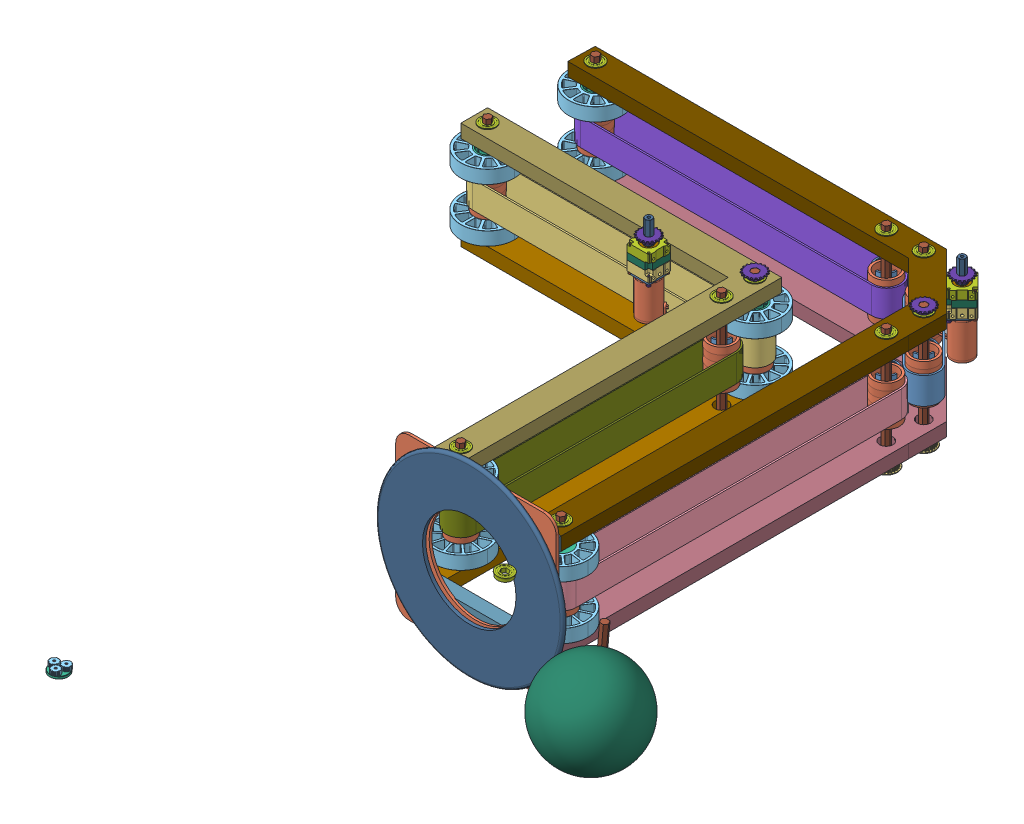
SolidWorks assembly Iteration3_v4, configuration Default. Lengths in mm.
Overall size (1189.44 656.85 1138.64).
276 component instances, 40 part files, 0 mates.
Components (placement in the parent):
- Iteration3_v4.step-1: Iteration3_v4.step [Default] at origin size (1189.44 656.85 1138.64)
  - Assembly 3 _2_.step-1: Assembly 3 _2_.step [Default] at origin size (67.31 38.1 67.31)
    - 2in Wheel Intergrated 0500 HEX Hub.STEP-1: 2in Wheel Intergrated 0500 HEX Hub.STEP [Default] at (23.3322 453.8443 -103.7275) x (1 0 0) z (0 -1 0) size (41.91 41.91 25.4)
    - 2in Tread.step-1: 2in Tread.step [Default] at (23.3322 453.8443 -103.7275) x (1 0 0) z (0 -1 0) size (50.8 50.8 25.4)
  - Assembly 3 _30_.step-1: Assembly 3 _30_.step [Default] at origin size (67.31 38.1 67.31)
    - 2in Tread.step-1: 2in Tread.step [Default] at (745.6616 401.2663 66.1079) x (1 0 0) z (0 -1 0) size (50.8 50.8 25.4)
    - 2in Wheel Intergrated 0500 HEX Hub.STEP-1: 2in Wheel Intergrated 0500 HEX Hub.STEP [Default] at (745.6616 401.2663 66.1079) x (1 0 0) z (0 -1 0) size (41.91 41.91 25.4)
  - belt pulley _4_.step-1: belt pulley _4_.step [Default] at origin size (42 14 42)
    - am-3403 24 tooth HTD pulley half 500hex.step-1: am-3403 24 tooth HTD pulley half 500hex.step [Default] at (745.7172 329.5288 -5.0591) x (0 1 0) z (-1 0 0) size (8.91 42 42)
    - am-3403 24 tooth HTD pulley half 500hex.step-2: am-3403 24 tooth HTD pulley half 500hex.step [Default] at (787.7172 329.5288 -5.0591) x (0 -1 0) z (1 0 0) size (8.91 42 42)
  - 217-4973_1stage_BAG _1_.step-1: 217-4973_1stage_BAG _1_.step [Default] at origin size (852.63 623.39 984.66)
    - 217-2820 Rev1_Public _1_.step-1: 217-2820 Rev1_Public _1_.step [Default] at origin size (852.63 582.79 973.43)
      - 217-2625-100 _1_.step-1: 217-2625-100 _1_.step [Default] at origin size (48.74 12.7 48.74)
        - 217-2625-010 Rev1.step-1: 217-2625-010 Rev1.step [Default] at (-51.7575 -31.3954 849.6821) x (0.784104 0 0.62063) z (0 1 0) size (4 4 12)
        - 217-2625-005 Rev1_Planet_Revolving_Follower01.step-1: 217-2625-005 Rev1_Planet_Revolving_Follower01.step [Default] at (-38.1283 -28.6954 860.4699) x (0.955071 0 0.296378) z (0 1 0) size (16.91 16.91 8)
        - 217-2625-010 Rev1.step-2: 217-2625-010 Rev1.step [Default] at (-35.3114 -31.3954 842.9076) x (0.795957 0 0.605353) z (0 1 0) size (4 4 12)
        - 217-2625-005 Rev1_Planet_Revolving_Follower01.step-2: 217-2625-005 Rev1_Planet_Revolving_Follower01.step [Default] at (-35.3114 -28.6954 842.9076) x (0.979261 0 0.202601) z (0 1 0) size (16.91 16.91 8)
        - 217-2625-010 Rev1.step-3: 217-2625-010 Rev1.step [Default] at (-38.1283 -31.3954 860.4699) x (0.784104 0 0.62063) z (0 1 0) size (4 4 12)
        - 217-2625-005 Rev1_Planet_Revolving_Follower01.step-3: 217-2625-005 Rev1_Planet_Revolving_Follower01.step [Default] at (-51.7575 -28.6954 849.6821) x (-0.955094 0 -0.296304) z (0 1 0) size (16.91 16.91 8)
        - 217-2625-008 Rev1.step-1: 217-2625-008 Rev1.step [Default] at (-41.6375 -35.0454 850.9) x (0.784104 0 0.62063) z (0 1 0) size (34.7 34.7 4.7)
      - 217-2625-026 Rev1.step-1: 217-2625-026 Rev1.step [Default] at (756.0539 522.2743 -67.5963) x (-0.707171 0 -0.707043) z (0 -1 0) size (44.45 42 18.12)
      - 217-2625-007 Rev1_Public.step-1: 217-2625-007 Rev1_Public.step [Default] at (756.0539 517.4197 -67.5963) x (0.418293 0 -0.908312) z (0 -1 0) size (15.29 15.29 12.7)
    - 217-2742-001 Rev4.step-1: 217-2742-001 Rev4.step [Default] at (756.0539 536.9745 -67.5963) x (0 1 0) z (0.707043 0 -0.707171) size (7 28 28)
    - 217-2625-003 Rev1.step-1: 217-2625-003 Rev1.step [Default] at (756.0539 536.2221 -67.5963) x (-0.707171 0 -0.707043) z (0 1 0) size (17 17 64.13)
    - 832-1750-Ring-Gear-Screw_SSA0832-0500ZC.step-1: 832-1750-Ring-Gear-Screw_SSA0832-0500ZC.step [Default] at (780.8026 498.0743 -67.5986) x (0.711223 0 -0.702967) z (-0.702967 0 -0.711223) size (6.73 48.51 6.73)
    - 217-4649-001 Rev1.step-1: 217-4649-001 Rev1.step [Default] at (756.0539 508.7283 -67.5963) x (-0.707171 0 -0.707043) z (0 1 0) size (18 18 13)
    - 217-2625-011 Rev1.step-1: 217-2625-011 Rev1.step [Default] at (756.0539 503.9925 -67.5963) x (0.707043 0 -0.707171) z (-0.707171 0 -0.707043) size (8.01 7.5 7.94)
    - 217-4649-007 Rev1_94105A824.step-1: 217-4649-007 Rev1_94105A824.step [Default] at (751.2576 503.2533 -62.7993) x (-0.062366 -0.996104 -0.062355) z (-0.707043 0 0.707171) size (4.83 4.83 4.77)
    - 217-2816-001 Rev1.step-1: 217-2816-001 Rev1.step [Default] at (756.0539 522.4243 -67.5963) x (-0.707171 0 -0.707043) z (0 1 0) size (42 42 14.52)
    - 217-2625-017 Rev1_9714K61.step-1: 217-2625-017 Rev1_9714K61.step [Default] at (755.8652 536.1943 -67.3014) x (0.983376 0 -0.181581) z (-0.181581 0 -0.983376) size (28.51 4.98 27.43)
    - 217-4649-002 Rev1_SSA0832-0500ZC.step-1: 217-4649-002 Rev1_SSA0832-0500ZC.step [Default] at (756.0516 495.0743 -92.9963) x (-0.426003 0 0.904722) z (0.904722 0 0.426003) size (6.73 16.76 6.73)
    - 217-4649-006 Rev1_SSA0004-008BA.step-1: 217-4649-006 Rev1_SSA0004-008BA.step [Default] at (747.2158 498.0743 -58.7567) x (0.258731 0 -0.965949) z (0.965949 0 0.258731) size (7 14 7)
    - 217-2822-003 Rev4.step-1: 217-2822-003 Rev4.step [Default] at (756.0539 496.5743 -67.5963) x (-0.707171 0 -0.707043) z (0 -1 0) size (42 42 4.8)
    - 217-4649-002 Rev1_SSA0832-0500ZC.step-2: 217-4649-002 Rev1_SSA0832-0500ZC.step [Default] at (756.0562 495.0743 -42.1964) x (-0.890925 0 0.454151) z (0.454151 0 0.890925) size (6.73 16.76 6.73)
    - 217-3351 Rev2.step-1: 217-3351 Rev2.step [Default] at (756.0539 495.0743 -67.5963) x (0.707043 0 -0.707171) z (0 1 0) size (59.1 59.1 84.5)
    - 217-2742-001 Rev4.step-2: 217-2742-001 Rev4.step [Default] at (756.0539 528.9745 -67.5963) x (0 1 0) z (0.6385 0 -0.769622) size (7 28 28)
    - 217-2625-025 Rev1.step-1: 217-2625-025 Rev1.step [Default] at (756.0539 505.5743 -67.5963) x (-0.707171 0 -0.707043) z (0 -1 0) size (44.45 42 18)
    - 217-4649-006 Rev1_SSA0004-008BA.step-2: 217-4649-006 Rev1_SSA0004-008BA.step [Default] at (764.8919 498.0743 -76.436) x (-0.258731 0 0.965949) z (-0.965949 0 -0.258731) size (7 14 7)
    - 217-2625-018 Rev1_98541A410.step-1: 217-2625-018 Rev1_98541A410.step [Default] at (756.0539 528.0697 -67.5963) x (0 1 0) z (0.694593 0 -0.719403) size (1 19.6 17.4)
    - 832-1750-Ring-Gear-Screw_SSA0832-0500ZC.step-2: 832-1750-Ring-Gear-Screw_SSA0832-0500ZC.step [Default] at (731.3051 498.0743 -67.5941) x (0.755856 0 0.654738) z (0.654738 0 -0.755856) size (6.73 48.51 6.73)
  - Assembly 3 _39_.step-1: Assembly 3 _39_.step [Default] at origin size (67.31 38.1 67.31)
    - 2in Tread.step-1: 2in Tread.step [Default] at (529.7616 401.2663 658.5687) x (1 0 0) z (0 -1 0) size (50.8 50.8 25.4)
    - 2in Wheel Intergrated 0500 HEX Hub.STEP-1: 2in Wheel Intergrated 0500 HEX Hub.STEP [Default] at (529.7616 401.2663 658.5687) x (1 0 0) z (0 -1 0) size (41.91 41.91 25.4)
  - belt pulley _1_.step-1: belt pulley _1_.step [Default] at origin size (42 14 42)
    - am-3403 24 tooth HTD pulley half 500hex.step-1: am-3403 24 tooth HTD pulley half 500hex.step [Default] at (618.1588 329.5288 -103.4764) x (0 -1 0) z (1 0 0) size (8.91 42 42)
    - am-3403 24 tooth HTD pulley half 500hex.step-2: am-3403 24 tooth HTD pulley half 500hex.step [Default] at (576.1588 329.5288 -103.4764) x (0 1 0) z (-1 0 0) size (8.91 42 42)
  - Assembly 3 _6_.step-1: Assembly 3 _6_.step [Default] at origin size (67.31 38.1 67.31)
    - 2in Tread.step-1: 2in Tread.step [Default] at (576.2037 426.6663 -103.4313) x (1 0 0) z (0 -1 0) size (50.8 50.8 25.4)
    - 2in Wheel Intergrated 0500 HEX Hub.STEP-1: 2in Wheel Intergrated 0500 HEX Hub.STEP [Default] at (576.2037 426.6663 -103.4313) x (1 0 0) z (0 -1 0) size (41.91 41.91 25.4)
  - Assembly 3 _25_.step-1: Assembly 3 _25_.step [Default] at origin size (67.31 38.1 67.31)
    - 2in Wheel Intergrated 0500 HEX Hub.STEP-1: 2in Wheel Intergrated 0500 HEX Hub.STEP [Default] at (576.2037 426.6663 -103.4313) x (1 0 0) z (0 -1 0) size (41.91 41.91 25.4)
    - 2in Tread.step-1: 2in Tread.step [Default] at (576.2037 426.6663 -103.4313) x (1 0 0) z (0 -1 0) size (50.8 50.8 25.4)
  - 217-4973_1stage_BAG _2_.step-1: 217-4973_1stage_BAG _2_.step [Default] at origin size (62.26 163.42 62.26)
    - 217-2820 Rev1_Public _1_-1.step-1: 217-2820 Rev1_Public _1_-1.step [Default] at origin size (46.71 36.33 46.71)
      - 217-2625-100 _1_-1.step-1: 217-2625-100 _1_-1.step [Default] at origin size (46.71 12.7 46.71)
        - 217-2625-010 Rev1.step-1: 217-2625-010 Rev1.step [Default] at (404.0227 521.7397 172.425) x (0.456494 0 0.889726) z (0 -1 0) size (4 4 12)
        - 217-2625-008 Rev1.step-1: 217-2625-008 Rev1.step [Default] at (395.3167 525.3897 167.1236) x (0.456494 0 0.889726) z (0 -1 0) size (34.7 34.7 4.7)
        - 217-2625-010 Rev1.step-2: 217-2625-010 Rev1.step [Default] at (396.0879 521.7397 156.9598) x (0.456494 0 0.889726) z (0 -1 0) size (4 4 12)
        - 217-2625-010 Rev1.step-3: 217-2625-010 Rev1.step [Default] at (386.2478 521.7397 171.7767) x (0.439206 0 0.898387) z (0 -1 0) size (4 4 12)
        - 217-2625-005 Rev1_Planet_Revolving_Follower01.step-1: 217-2625-005 Rev1_Planet_Revolving_Follower01.step [Default] at (396.0879 519.0397 156.9598) x (-0.105131 0 -0.994458) z (0 -1 0) size (16.91 16.91 8)
        - 217-2625-005 Rev1_Planet_Revolving_Follower01.step-2: 217-2625-005 Rev1_Planet_Revolving_Follower01.step [Default] at (404.0227 519.0397 172.425) x (0.105209 0 0.99445) z (0 -1 0) size (16.91 16.91 8)
        - 217-2625-005 Rev1_Planet_Revolving_Follower01.step-3: 217-2625-005 Rev1_Planet_Revolving_Follower01.step [Default] at (386.2478 519.0397 171.7767) x (0.008519 0 0.999964) z (0 -1 0) size (16.91 16.91 8)
      - 217-2625-007 Rev1_Public.step-1: 217-2625-007 Rev1_Public.step [Default] at (395.3167 518.6897 167.1236) x (0.34641 0 0.938083) z (0 -1 0) size (15.29 15.29 12.7)
      - 217-2625-026 Rev1.step-1: 217-2625-026 Rev1.step [Default] at (395.3167 523.5443 167.1236) x (1 0 0) z (0 -1 0) size (44.45 42 18.12)
    - 832-1750-Ring-Gear-Screw_SSA0832-0500ZC.step-1: 832-1750-Ring-Gear-Screw_SSA0832-0500ZC.step [Default] at (377.8167 499.3443 184.6236) x (-0.005929 0 0.999982) z (0.999982 0 0.005929) size (6.73 48.51 6.73)
    - 217-2625-003 Rev1.step-1: 217-2625-003 Rev1.step [Default] at (395.3167 537.4921 167.1236) x (1 0 0) z (0 1 0) size (17 17 64.13)
    - 217-4649-007 Rev1_94105A824.step-1: 217-4649-007 Rev1_94105A824.step [Default] at (395.3167 504.5233 160.3401) x (0.088191 -0.996104 0) z (0 0 -1) size (4.83 4.83 4.77)
    - 217-4649-006 Rev1_SSA0004-008BA.step-1: 217-4649-006 Rev1_SSA0004-008BA.step [Default] at (395.3167 499.3443 179.6236) x (-0.5 0 -0.866025) z (0.866025 0 -0.5) size (7 14 7)
    - 217-4649-001 Rev1.step-1: 217-4649-001 Rev1.step [Default] at (395.3167 509.9983 167.1236) x (1 0 0) z (0 1 0) size (18 18 13)
    - 217-2742-001 Rev4.step-1: 217-2742-001 Rev4.step [Default] at (395.3167 538.2445 167.1236) x (0 1 0) z (0 0 1) size (7 28 28)
    - 217-2816-001 Rev1.step-1: 217-2816-001 Rev1.step [Default] at (395.3167 523.6943 167.1236) x (1 0 0) z (0 1 0) size (42 42 14.52)
    - 217-2742-001 Rev4.step-2: 217-2742-001 Rev4.step [Default] at (395.3167 530.2445 167.1236) x (0 1 0) z (0.092627 0 0.995701) size (7 28 28)
    - 217-2822-003 Rev4.step-1: 217-2822-003 Rev4.step [Default] at (395.3167 497.8443 167.1236) x (1 0 0) z (0 -1 0) size (42 42 4.8)
    - 217-4649-002 Rev1_SSA0832-0500ZC.step-1: 217-4649-002 Rev1_SSA0832-0500ZC.step [Default] at (377.3562 496.3443 149.1631) x (0.308932 0 -0.951084) z (-0.951084 0 -0.308932) size (6.73 16.76 6.73)
    - 217-4649-002 Rev1_SSA0832-0500ZC.step-2: 217-4649-002 Rev1_SSA0832-0500ZC.step [Default] at (413.2773 496.3443 185.0841) x (-0.33842 0 -0.940995) z (-0.940995 0 0.33842) size (6.73 16.76 6.73)
    - 832-1750-Ring-Gear-Screw_SSA0832-0500ZC.step-2: 832-1750-Ring-Gear-Screw_SSA0832-0500ZC.step [Default] at (412.8167 499.3443 149.6236) x (-0.997447 0 0.071411) z (0.071411 0 0.997447) size (6.73 48.51 6.73)
    - 217-4649-006 Rev1_SSA0004-008BA.step-2: 217-4649-006 Rev1_SSA0004-008BA.step [Default] at (395.3167 499.3443 154.6236) x (0.5 0 0.866025) z (-0.866025 0 0.5) size (7 14 7)
    - 217-2625-017 Rev1_9714K61.step-1: 217-2625-017 Rev1_9714K61.step [Default] at (395.2416 537.4643 166.7816) x (-0.56703 0 0.823697) z (0.823697 0 0.56703) size (28.51 4.98 27.43)
    - 217-2625-018 Rev1_98541A410.step-1: 217-2625-018 Rev1_98541A410.step [Default] at (395.3167 529.3397 167.1236) x (0 1 0) z (0.017452 0 0.999848) size (1 19.6 17.4)
    - 217-2625-025 Rev1.step-1: 217-2625-025 Rev1.step [Default] at (395.3167 506.8443 167.1236) x (1 0 0) z (0 -1 0) size (44.45 42 18)
    - 217-2625-011 Rev1.step-1: 217-2625-011 Rev1.step [Default] at (395.3167 505.2625 167.1236) x (0 0 1) z (1 0 0) size (8.01 7.5 7.94)
    - 217-3351 Rev2.step-1: 217-3351 Rev2.step [Default] at (395.3167 496.3443 167.1236) x (0 0 1) z (0 1 0) size (59.1 59.1 84.5)
  - Assembly 3 _1_.step-1: Assembly 3 _1_.step [Default] at origin size (67.31 38.1 67.31)
    - 2in Wheel Intergrated 0500 HEX Hub.STEP-1: 2in Wheel Intergrated 0500 HEX Hub.STEP [Default] at (23.3322 428.4443 -103.7275) x (1 0 0) z (0 -1 0) size (41.91 41.91 25.4)
    - 2in Tread.step-1: 2in Tread.step [Default] at (23.3322 428.4443 -103.7275) x (1 0 0) z (0 -1 0) size (50.8 50.8 25.4)
  - Assembly 3 _3_.step-1: Assembly 3 _3_.step [Default] at origin size (67.31 38.1 67.31)
    - 2in Tread.step-1: 2in Tread.step [Default] at (23.3322 403.0443 -103.7275) x (1 0 0) z (0 -1 0) size (50.8 50.8 25.4)
    - 2in Wheel Intergrated 0500 HEX Hub.STEP-1: 2in Wheel Intergrated 0500 HEX Hub.STEP [Default] at (23.3322 403.0443 -103.7275) x (1 0 0) z (0 -1 0) size (41.91 41.91 25.4)
  - Assembly 3 _23_.step-1: Assembly 3 _23_.step [Default] at origin size (67.31 38.1 67.31)
    - 2in Wheel Intergrated 0500 HEX Hub.STEP-1: 2in Wheel Intergrated 0500 HEX Hub.STEP [Default] at (576.2037 452.0663 -103.4313) x (1 0 0) z (0 -1 0) size (41.91 41.91 25.4)
    - 2in Tread.step-1: 2in Tread.step [Default] at (576.2037 452.0663 -103.4313) x (1 0 0) z (0 -1 0) size (50.8 50.8 25.4)
  - Assembly 3 _20_.step-1: Assembly 3 _20_.step [Default] at origin size (67.31 38.1 67.31)
    - 2in Tread.step-1: 2in Tread.step [Default] at (529.7616 401.2663 163.2687) x (1 0 0) z (0 -1 0) size (50.8 50.8 25.4)
    - 2in Wheel Intergrated 0500 HEX Hub.STEP-1: 2in Wheel Intergrated 0500 HEX Hub.STEP [Default] at (529.7616 401.2663 163.2687) x (1 0 0) z (0 -1 0) size (41.91 41.91 25.4)
  - Assembly 3 _26_.step-1: Assembly 3 _26_.step [Default] at origin size (67.31 38.1 67.31)
    - 2in Tread.step-1: 2in Tread.step [Default] at (647.3349 452.0663 -103.4314) x (1 0 0) z (0 -1 0) size (50.8 50.8 25.4)
    - 2in Wheel Intergrated 0500 HEX Hub.STEP-1: 2in Wheel Intergrated 0500 HEX Hub.STEP [Default] at (647.3349 452.0663 -103.4314) x (1 0 0) z (0 -1 0) size (41.91 41.91 25.4)
  - Assembly 3 _33_.step-1: Assembly 3 _33_.step [Default] at origin size (67.31 38.1 67.31)
    - 2in Tread.step-1: 2in Tread.step [Default] at (745.7621 401.2663 -5.014) x (1 0 0) z (0 -1 0) size (50.8 50.8 25.4)
    - 2in Wheel Intergrated 0500 HEX Hub.STEP-1: 2in Wheel Intergrated 0500 HEX Hub.STEP [Default] at (745.7621 401.2663 -5.014) x (1 0 0) z (0 -1 0) size (41.91 41.91 25.4)
  - am-3480 4IN 500Hex Bore Compliant Wheel REV2 _4_.step-1: am-3480 4IN 500Hex Bore Compliant Wheel REV2 _4_.step [Default] at origin size (578.18 128.78 275.25)
    - 4IN Compliant Wheel FINAL Overmold.STEP-1: 4IN Compliant Wheel FINAL Overmold.STEP [Default] at (44.2874 479.2443 -82.7726) x (1 0 0) z (0 -1 0) size (101.6 101.6 25.4)
    - 2in Wheel Intergrated 0500 HEX Hub-0.step-1: 2in Wheel Intergrated 0500 HEX Hub-0.step [Default] at (550.7167 388.5663 120.7236) x (-1 0 0) z (0 -1 0) size (41.91 41.91 25.4)
  - Assembly 3 _10_.step-1: Assembly 3 _10_.step [Default] at origin size (67.31 38.1 67.31)
    - 2in Wheel Intergrated 0500 HEX Hub.STEP-1: 2in Wheel Intergrated 0500 HEX Hub.STEP [Default] at (745.7621 426.6663 -5.014) x (1 0 0) z (0 -1 0) size (41.91 41.91 25.4)
    - 2in Tread.step-1: 2in Tread.step [Default] at (745.7621 426.6663 -5.014) x (1 0 0) z (0 -1 0) size (50.8 50.8 25.4)
  - Assembly 3 _22_.step-1: Assembly 3 _22_.step [Default] at origin size (67.31 38.1 67.31)
    - 2in Wheel Intergrated 0500 HEX Hub.STEP-1: 2in Wheel Intergrated 0500 HEX Hub.STEP [Default] at (529.7616 426.6663 163.2687) x (1 0 0) z (0 -1 0) size (41.91 41.91 25.4)
    - 2in Tread.step-1: 2in Tread.step [Default] at (529.7616 426.6663 163.2687) x (1 0 0) z (0 -1 0) size (50.8 50.8 25.4)
  - Assembly 3 _21_.step-1: Assembly 3 _21_.step [Default] at origin size (67.31 38.1 67.31)
    - 2in Wheel Intergrated 0500 HEX Hub.STEP-1: 2in Wheel Intergrated 0500 HEX Hub.STEP [Default] at (529.7616 452.0663 163.2687) x (1 0 0) z (0 -1 0) size (41.91 41.91 25.4)
    - 2in Tread.step-1: 2in Tread.step [Default] at (529.7616 452.0663 163.2687) x (1 0 0) z (0 -1 0) size (50.8 50.8 25.4)
  - Assembly 3 _32_.step-1: Assembly 3 _32_.step [Default] at origin size (67.31 38.1 67.31)
    - 2in Wheel Intergrated 0500 HEX Hub.STEP-1: 2in Wheel Intergrated 0500 HEX Hub.STEP [Default] at (745.7621 452.0663 -5.014) x (1 0 0) z (0 -1 0) size (41.91 41.91 25.4)
    - 2in Tread.step-1: 2in Tread.step [Default] at (745.7621 452.0663 -5.014) x (1 0 0) z (0 -1 0) size (50.8 50.8 25.4)
  - Assembly 3 _13_.step-1: Assembly 3 _13_.step [Default] at origin size (67.31 38.1 67.31)
    - 2in Wheel Intergrated 0500 HEX Hub.STEP-1: 2in Wheel Intergrated 0500 HEX Hub.STEP [Default] at (745.6778 426.6663 683.9525) x (1 0 0) z (0 -1 0) size (41.91 41.91 25.4)
    - 2in Tread.step-1: 2in Tread.step [Default] at (745.6778 426.6663 683.9525) x (1 0 0) z (0 -1 0) size (50.8 50.8 25.4)
  - Assembly 3 _19_.step-1: Assembly 3 _19_.step [Default] at origin size (67.31 38.1 67.31)
    - 2in Tread.step-1: 2in Tread.step [Default] at (529.7616 426.6663 99.7687) x (1 0 0) z (0 -1 0) size (50.8 50.8 25.4)
    - 2in Wheel Intergrated 0500 HEX Hub.STEP-1: 2in Wheel Intergrated 0500 HEX Hub.STEP [Default] at (529.7616 426.6663 99.7687) x (1 0 0) z (0 -1 0) size (41.91 41.91 25.4)
  - Assembly 3 _12_.step-1: Assembly 3 _12_.step [Default] at origin size (67.31 38.1 67.31)
    - 2in Tread.step-1: 2in Tread.step [Default] at (529.7616 426.6663 658.5687) x (1 0 0) z (0 -1 0) size (50.8 50.8 25.4)
    - 2in Wheel Intergrated 0500 HEX Hub.STEP-1: 2in Wheel Intergrated 0500 HEX Hub.STEP [Default] at (529.7616 426.6663 658.5687) x (1 0 0) z (0 -1 0) size (41.91 41.91 25.4)
  - Assembly 3 _28_.step-1: Assembly 3 _28_.step [Default] at origin size (67.31 38.1 67.31)
    - 2in Wheel Intergrated 0500 HEX Hub.STEP-1: 2in Wheel Intergrated 0500 HEX Hub.STEP [Default] at (647.3349 426.6663 -103.4314) x (1 0 0) z (0 -1 0) size (41.91 41.91 25.4)
    - 2in Tread.step-1: 2in Tread.step [Default] at (647.3349 426.6663 -103.4314) x (1 0 0) z (0 -1 0) size (50.8 50.8 25.4)
  - Assembly 3 _38_.step-1: Assembly 3 _38_.step [Default] at origin size (67.31 38.1 67.31)
    - 2in Tread.step-1: 2in Tread.step [Default] at (529.7616 452.0663 658.5687) x (1 0 0) z (0 -1 0) size (50.8 50.8 25.4)
    - 2in Wheel Intergrated 0500 HEX Hub.STEP-1: 2in Wheel Intergrated 0500 HEX Hub.STEP [Default] at (529.7616 452.0663 658.5687) x (1 0 0) z (0 -1 0) size (41.91 41.91 25.4)
  - Assembly 3 _8_.step-1: Assembly 3 _8_.step [Default] at origin size (67.31 38.1 67.31)
    - 2in Wheel Intergrated 0500 HEX Hub.STEP-1: 2in Wheel Intergrated 0500 HEX Hub.STEP [Default] at (647.3349 426.6663 -103.4314) x (1 0 0) z (0 -1 0) size (41.91 41.91 25.4)
    - 2in Tread.step-1: 2in Tread.step [Default] at (647.3349 426.6663 -103.4314) x (1 0 0) z (0 -1 0) size (50.8 50.8 25.4)
  - Assembly 3 _24_.step-1: Assembly 3 _24_.step [Default] at origin size (67.31 38.1 67.31)
    - 2in Wheel Intergrated 0500 HEX Hub.STEP-1: 2in Wheel Intergrated 0500 HEX Hub.STEP [Default] at (576.2037 401.2663 -103.4313) x (1 0 0) z (0 -1 0) size (41.91 41.91 25.4)
    - 2in Tread.step-1: 2in Tread.step [Default] at (576.2037 401.2663 -103.4313) x (1 0 0) z (0 -1 0) size (50.8 50.8 25.4)
  - Assembly 3 _9_.step-1: Assembly 3 _9_.step [Default] at origin size (67.31 38.1 67.31)
    - 2in Wheel Intergrated 0500 HEX Hub.STEP-1: 2in Wheel Intergrated 0500 HEX Hub.STEP [Default] at (529.7616 426.6663 163.2687) x (1 0 0) z (0 -1 0) size (41.91 41.91 25.4)
    - 2in Tread.step-1: 2in Tread.step [Default] at (529.7616 426.6663 163.2687) x (1 0 0) z (0 -1 0) size (50.8 50.8 25.4)
  - Assembly 3 _34_.step-1: Assembly 3 _34_.step [Default] at origin size (67.31 38.1 67.31)
    - 2in Wheel Intergrated 0500 HEX Hub.STEP-1: 2in Wheel Intergrated 0500 HEX Hub.STEP [Default] at (745.7621 426.6663 -5.014) x (1 0 0) z (0 -1 0) size (41.91 41.91 25.4)
    - 2in Tread.step-1: 2in Tread.step [Default] at (745.7621 426.6663 -5.014) x (1 0 0) z (0 -1 0) size (50.8 50.8 25.4)
  - Assembly 3 _7_.step-1: Assembly 3 _7_.step [Default] at origin size (67.31 38.1 67.31)
    - 2in Wheel Intergrated 0500 HEX Hub.STEP-1: 2in Wheel Intergrated 0500 HEX Hub.STEP [Default] at (529.7616 426.6663 99.7687) x (1 0 0) z (0 -1 0) size (41.91 41.91 25.4)
    - 2in Tread.step-1: 2in Tread.step [Default] at (529.7616 426.6663 99.7687) x (1 0 0) z (0 -1 0) size (50.8 50.8 25.4)
  - Assembly 3 _36_.step-1: Assembly 3 _36_.step [Default] at origin size (67.31 38.1 67.31)
    - 2in Wheel Intergrated 0500 HEX Hub.STEP-1: 2in Wheel Intergrated 0500 HEX Hub.STEP [Default] at (745.6778 401.2663 683.9525) x (1 0 0) z (0 -1 0) size (41.91 41.91 25.4)
    - 2in Tread.step-1: 2in Tread.step [Default] at (745.6778 401.2663 683.9525) x (1 0 0) z (0 -1 0) size (50.8 50.8 25.4)
  - am-3480 4IN 500Hex Bore Compliant Wheel REV2 _5_.step-1: am-3480 4IN 500Hex Bore Compliant Wheel REV2 _5_.step [Default] at origin size (101.6 127 101.6)
    - 2in Wheel Intergrated 0500 HEX Hub-0.step-1: 2in Wheel Intergrated 0500 HEX Hub-0.step [Default] at (550.7168 490.1663 120.7236) x (-1 0 0) z (0 -1 0) size (41.91 41.91 25.4)
    - 4IN Compliant Wheel FINAL Overmold.STEP-1: 4IN Compliant Wheel FINAL Overmold.STEP [Default] at (550.7167 375.8663 120.7236) x (1 0 0) z (0 -1 0) size (101.6 101.6 25.4)
  - Assembly 3 _14_.step-1: Assembly 3 _14_.step [Default] at origin size (67.31 38.1 67.31)
    - 2in Tread.step-1: 2in Tread.step [Default] at (21.7616 452.0663 99.7687) x (1 0 0) z (0 -1 0) size (50.8 50.8 25.4)
    - 2in Wheel Intergrated 0500 HEX Hub.STEP-1: 2in Wheel Intergrated 0500 HEX Hub.STEP [Default] at (21.7616 452.0663 99.7687) x (1 0 0) z (0 -1 0) size (41.91 41.91 25.4)
  - Assembly 3 _37_.step-1: Assembly 3 _37_.step [Default] at origin size (67.31 38.1 67.31)
    - 2in Tread.step-1: 2in Tread.step [Default] at (745.6778 426.6663 683.9525) x (1 0 0) z (0 -1 0) size (50.8 50.8 25.4)
    - 2in Wheel Intergrated 0500 HEX Hub.STEP-1: 2in Wheel Intergrated 0500 HEX Hub.STEP [Default] at (745.6778 426.6663 683.9525) x (1 0 0) z (0 -1 0) size (41.91 41.91 25.4)
  - Assembly 3 _16_.step-1: Assembly 3 _16_.step [Default] at origin size (67.31 38.1 67.31)
    - 2in Tread.step-1: 2in Tread.step [Default] at (21.7616 426.6663 99.7687) x (1 0 0) z (0 -1 0) size (50.8 50.8 25.4)
    - 2in Wheel Intergrated 0500 HEX Hub.STEP-1: 2in Wheel Intergrated 0500 HEX Hub.STEP [Default] at (21.7616 426.6663 99.7687) x (1 0 0) z (0 -1 0) size (41.91 41.91 25.4)
  - Assembly 3 _31_.step-1: Assembly 3 _31_.step [Default] at origin size (67.31 38.1 67.31)
    - 2in Tread.step-1: 2in Tread.step [Default] at (745.6616 426.6663 66.1079) x (1 0 0) z (0 -1 0) size (50.8 50.8 25.4)
    - 2in Wheel Intergrated 0500 HEX Hub.STEP-1: 2in Wheel Intergrated 0500 HEX Hub.STEP [Default] at (745.6616 426.6663 66.1079) x (1 0 0) z (0 -1 0) size (41.91 41.91 25.4)
  - Assembly 3 _29_.step-1: Assembly 3 _29_.step [Default] at origin size (67.31 38.1 67.31)
    - 2in Tread.step-1: 2in Tread.step [Default] at (745.6616 452.0663 66.1079) x (1 0 0) z (0 -1 0) size (50.8 50.8 25.4)
    - 2in Wheel Intergrated 0500 HEX Hub.STEP-1: 2in Wheel Intergrated 0500 HEX Hub.STEP [Default] at (745.6616 452.0663 66.1079) x (1 0 0) z (0 -1 0) size (41.91 41.91 25.4)
  - belt pulley _3_.step-1: belt pulley _3_.step [Default] at origin size (42 14 42)
    - am-3403 24 tooth HTD pulley half 500hex.step-1: am-3403 24 tooth HTD pulley half 500hex.step [Default] at (745.6167 329.5288 66.0628) x (0 1 0) z (-1 0 0) size (8.91 42 42)
    - am-3403 24 tooth HTD pulley half 500hex.step-2: am-3403 24 tooth HTD pulley half 500hex.step [Default] at (787.6167 329.5288 66.0628) x (0 -1 0) z (1 0 0) size (8.91 42 42)
  - am-3480 4IN 500Hex Bore Compliant Wheel REV2 _2_.step-1: am-3480 4IN 500Hex Bore Compliant Wheel REV2 _2_.step [Default] at origin size (101.6 25.4 101.6)
    - 4IN Compliant Wheel FINAL Overmold.STEP-1: 4IN Compliant Wheel FINAL Overmold.STEP [Default] at (42.7167 375.8663 120.7236) x (1 0 0) z (0 -1 0) size (101.6 101.6 25.4)
    - 2in Wheel Intergrated 0500 HEX Hub-0.step-1: 2in Wheel Intergrated 0500 HEX Hub-0.step [Default] at (42.7167 388.5663 120.7236) x (-1 0 0) z (0 -1 0) size (41.91 41.91 25.4)
  - Assembly 3 _5_.step-1: Assembly 3 _5_.step [Default] at origin size (67.31 38.1 67.31)
    - 2in Wheel Intergrated 0500 HEX Hub.STEP-1: 2in Wheel Intergrated 0500 HEX Hub.STEP [Default] at (21.7616 426.6663 99.7687) x (1 0 0) z (0 -1 0) size (41.91 41.91 25.4)
    - 2in Tread.step-1: 2in Tread.step [Default] at (21.7616 426.6663 99.7687) x (1 0 0) z (0 -1 0) size (50.8 50.8 25.4)
  - Assembly 3 _18_.step-1: Assembly 3 _18_.step [Default] at origin size (67.31 38.1 67.31)
    - 2in Wheel Intergrated 0500 HEX Hub.STEP-1: 2in Wheel Intergrated 0500 HEX Hub.STEP [Default] at (529.7616 401.2663 99.7687) x (1 0 0) z (0 -1 0) size (41.91 41.91 25.4)
    - 2in Tread.step-1: 2in Tread.step [Default] at (529.7616 401.2663 99.7687) x (1 0 0) z (0 -1 0) size (50.8 50.8 25.4)
  - Assembly 3 _27_.step-1: Assembly 3 _27_.step [Default] at origin size (67.31 38.1 67.31)
    - 2in Tread.step-1: 2in Tread.step [Default] at (647.3349 401.2663 -103.4314) x (1 0 0) z (0 -1 0) size (50.8 50.8 25.4)
    - 2in Wheel Intergrated 0500 HEX Hub.STEP-1: 2in Wheel Intergrated 0500 HEX Hub.STEP [Default] at (647.3349 401.2663 -103.4314) x (1 0 0) z (0 -1 0) size (41.91 41.91 25.4)
  - Assembly 3 _35_.step-1: Assembly 3 _35_.step [Default] at origin size (67.31 38.1 67.31)
    - 2in Tread.step-1: 2in Tread.step [Default] at (745.6778 452.0663 683.9525) x (1 0 0) z (0 -1 0) size (50.8 50.8 25.4)
    - 2in Wheel Intergrated 0500 HEX Hub.STEP-1: 2in Wheel Intergrated 0500 HEX Hub.STEP [Default] at (745.6778 452.0663 683.9525) x (1 0 0) z (0 -1 0) size (41.91 41.91 25.4)
  - am-3480 4IN 500Hex Bore Compliant Wheel REV2 _6_.step-1: am-3480 4IN 500Hex Bore Compliant Wheel REV2 _6_.step [Default] at origin size (579.76 25.4 101.6)
    - 2in Wheel Intergrated 0500 HEX Hub-0.step-1: 2in Wheel Intergrated 0500 HEX Hub-0.step [Default] at (42.7167 490.1663 120.7236) x (-1 0 0) z (0 -1 0) size (41.91 41.91 25.4)
    - 4IN Compliant Wheel FINAL Overmold.STEP-1: 4IN Compliant Wheel FINAL Overmold.STEP [Default] at (550.7168 477.4663 120.7236) x (1 0 0) z (0 -1 0) size (101.6 101.6 25.4)
  - Assembly 3 _15_.step-1: Assembly 3 _15_.step [Default] at origin size (67.31 38.1 67.31)
    - 2in Tread.step-1: 2in Tread.step [Default] at (21.7616 401.2663 99.7687) x (1 0 0) z (0 -1 0) size (50.8 50.8 25.4)
    - 2in Wheel Intergrated 0500 HEX Hub.STEP-1: 2in Wheel Intergrated 0500 HEX Hub.STEP [Default] at (21.7616 401.2663 99.7687) x (1 0 0) z (0 -1 0) size (41.91 41.91 25.4)
  - Assembly 3 _11_.step-1: Assembly 3 _11_.step [Default] at origin size (67.31 38.1 67.31)
    - 2in Wheel Intergrated 0500 HEX Hub.STEP-1: 2in Wheel Intergrated 0500 HEX Hub.STEP [Default] at (745.6616 426.6663 66.1079) x (1 0 0) z (0 -1 0) size (41.91 41.91 25.4)
    - 2in Tread.step-1: 2in Tread.step [Default] at (745.6616 426.6663 66.1079) x (1 0 0) z (0 -1 0) size (50.8 50.8 25.4)
  - Assembly 3 _40_.step-1: Assembly 3 _40_.step [Default] at origin size (67.31 38.1 67.31)
    - 2in Wheel Intergrated 0500 HEX Hub.STEP-1: 2in Wheel Intergrated 0500 HEX Hub.STEP [Default] at (529.7616 426.6663 658.5687) x (1 0 0) z (0 -1 0) size (41.91 41.91 25.4)
    - 2in Tread.step-1: 2in Tread.step [Default] at (529.7616 426.6663 658.5687) x (1 0 0) z (0 -1 0) size (50.8 50.8 25.4)
  - Assembly 3 _4_.step-1: Assembly 3 _4_.step [Default] at origin size (67.31 38.1 67.31)
    - 2in Wheel Intergrated 0500 HEX Hub.STEP-1: 2in Wheel Intergrated 0500 HEX Hub.STEP [Default] at (23.3322 428.4443 -103.7275) x (1 0 0) z (0 -1 0) size (41.91 41.91 25.4)
    - 2in Tread.step-1: 2in Tread.step [Default] at (23.3322 428.4443 -103.7275) x (1 0 0) z (0 -1 0) size (50.8 50.8 25.4)
  - am-3480 4IN 500Hex Bore Compliant Wheel REV2 _1_.step-1: am-3480 4IN 500Hex Bore Compliant Wheel REV2 _1_.step [Default] at origin size (101.6 25.4 101.6)
    - 2in Wheel Intergrated 0500 HEX Hub-0.step-1: 2in Wheel Intergrated 0500 HEX Hub-0.step [Default] at (44.2874 390.3443 -82.7726) x (-1 0 0) z (0 -1 0) size (41.91 41.91 25.4)
    - 4IN Compliant Wheel FINAL Overmold.STEP-1: 4IN Compliant Wheel FINAL Overmold.STEP [Default] at (44.2873 377.6443 -82.7726) x (1 0 0) z (0 -1 0) size (101.6 101.6 25.4)
  - belt pulley _2_.step-1: belt pulley _2_.step [Default] at origin size (42 14 42)
    - am-3403 24 tooth HTD pulley half 500hex.step-1: am-3403 24 tooth HTD pulley half 500hex.step [Default] at (689.2899 329.5288 -103.4764) x (0 -1 0) z (1 0 0) size (8.91 42 42)
    - am-3403 24 tooth HTD pulley half 500hex.step-2: am-3403 24 tooth HTD pulley half 500hex.step [Default] at (647.2899 329.5288 -103.4764) x (0 1 0) z (-1 0 0) size (8.91 42 42)
  - Assembly 3 _17_.step-1: Assembly 3 _17_.step [Default] at origin size (67.31 38.1 67.31)
    - 2in Tread.step-1: 2in Tread.step [Default] at (529.7616 452.0663 99.7687) x (1 0 0) z (0 -1 0) size (50.8 50.8 25.4)
    - 2in Wheel Intergrated 0500 HEX Hub.STEP-1: 2in Wheel Intergrated 0500 HEX Hub.STEP [Default] at (529.7616 452.0663 99.7687) x (1 0 0) z (0 -1 0) size (41.91 41.91 25.4)
  - am-3480 4IN 500Hex Bore Compliant Wheel REV2 _3_.step-1: am-3480 4IN 500Hex Bore Compliant Wheel REV2 _3_.step [Default] at origin size (101.6 27.18 275.25)
    - 2in Wheel Intergrated 0500 HEX Hub-0.step-1: 2in Wheel Intergrated 0500 HEX Hub-0.step [Default] at (44.2874 491.9443 -82.7726) x (-1 0 0) z (0 -1 0) size (41.91 41.91 25.4)
    - 4IN Compliant Wheel FINAL Overmold.STEP-1: 4IN Compliant Wheel FINAL Overmold.STEP [Default] at (42.7167 477.4663 120.7236) x (1 0 0) z (0 -1 0) size (101.6 101.6 25.4)
  - Cut-Extrude1.step-1: Cut-Extrude1.step [Default] at (766.6329 536.5848 704.9075) x (1 0 0) z (0 1 0) size (31.12 31.12 7.94)
  - am-3403 24 tooth HTD pulley half 500hex.step-1: am-3403 24 tooth HTD pulley half 500hex.step [Default] at (529.7167 330.7988 163.2236) x (0 1 0) z (-1 0 0) size (8.91 42 42)
  - 4IN Compliant Wheel FINAL Overmold.STEP-1: 4IN Compliant Wheel FINAL Overmold.STEP [Default] at (766.6329 502.8663 704.9075) x (1 0 0) z (0 1 0) size (101.6 101.6 25.4)
  - Belt 1.step-1: Belt 1.step [Default] at (127.8426 466.5443 -88.9391) size (610.03 50.8 57.15)
  - 4IN Compliant Wheel FINAL Overmold.STEP-2: 4IN Compliant Wheel FINAL Overmold.STEP [Default] at (550.7167 502.8663 679.5236) x (1 0 0) z (0 1 0) size (101.6 101.6 25.4)
  - Cut-Extrude1.step-2: Cut-Extrude1.step [Default] at (778.0486 517.3294 823.9997) x (-0.996195 0.087156 0) z (0.087156 0.996195 0) size (31.12 31.12 7.94)
  - Cut-Extrude1.step-3: Cut-Extrude1.step [Default] at (897.6808 283.0081 770.6513) x (-0.996195 0.087156 0) z (-0.087156 -0.996195 0) size (31.12 31.12 7.94)
  - Cut-Extrude1.step-4: Cut-Extrude1.step [Default] at (766.7172 345.7038 15.9409) x (1 0 0) z (0 -1 0) size (31.12 31.12 7.94)
  - Elevator 4.step-1: Elevator 4.step [Default] at (20.7439 542.7443 161.9297) size (558.8 25.4 635)
  - Lazy Susan Square.step-1: Lazy Susan Square.step [Default] at (659.8333 441.6504 772.7042) x (1 0 0) z (0 0 -1) size (355.6 355.6 12.7)
  - Hex Shaft_9.step-1: Hex Shaft_9.step [Default] at (766.6167 553.6663 87.0628) size (14.69 228.6 12.73)
  - Cut-Extrude1.step-5: Cut-Extrude1.step [Default] at (766.6329 345.7038 704.9075) x (1 0 0) z (0 -1 0) size (31.12 31.12 7.94)
  - Elevator 2.step-1: Elevator 2.step [Default] at (20.7439 542.7443 161.9297) size (558.8 25.4 635)
  - 2in Wheel Intergrated 0500 HEX Hub-0.step-1: 2in Wheel Intergrated 0500 HEX Hub-0.step [Default] at (766.6329 388.5663 704.9075) x (1 0 0) z (0 1 0) size (41.91 41.91 25.4)
  - Hex Shaft_9.step-2: Hex Shaft_9.step [Default] at (766.7172 553.6663 15.9409) size (14.69 228.6 12.73)
  - 4IN Compliant Wheel FINAL Overmold.STEP-3: 4IN Compliant Wheel FINAL Overmold.STEP [Default] at (550.7167 401.2663 679.5236) x (1 0 0) z (0 1 0) size (101.6 101.6 25.4)
  - Cut-Extrude1.step-6: Cut-Extrude1.step [Default] at (597.1588 345.7038 -82.4764) x (1 0 0) z (0 -1 0) size (31.12 31.12 7.94)
  - Elevator 3.step-1: Elevator 3.step [Default] at (20.7439 542.7443 161.9297) size (774.79 25.4 838.18)
  - Shooter Support.step-1: Shooter Support.step [Default] at (589.6773 542.7443 735.2568) size (266.7 25.4 25.4)
  - Cut-Extrude1.step-7: Cut-Extrude1.step [Default] at (44.2874 345.7038 -82.7726) x (1 0 0) z (0 -1 0) size (31.12 31.12 7.94)
  - Hex Shaft_9.step-3: Hex Shaft_9.step [Default] at (42.7167 553.6663 120.7236) size (14.69 228.6 12.73)
  - 2in Wheel Intergrated 0500 HEX Hub-0.step-2: 2in Wheel Intergrated 0500 HEX Hub-0.step [Default] at (550.7167 490.1663 679.5236) x (1 0 0) z (0 1 0) size (41.91 41.91 25.4)
  - Ball.step-1: Ball.step [Default] at (1034.5263 468.031 827.2699) size (177.8 177.8 177.8)
  - Hex Shaft_9.step-4: Hex Shaft_9.step [Default] at (668.2899 553.6663 -82.4764) size (14.69 228.6 12.73)
  - 4IN Compliant Wheel FINAL Overmold.STEP-4: 4IN Compliant Wheel FINAL Overmold.STEP [Default] at (766.6329 401.2663 704.9075) x (1 0 0) z (0 1 0) size (101.6 101.6 25.4)
  - Cut-Extrude1.step-8: Cut-Extrude1.step [Default] at (42.7167 536.5848 120.7236) x (1 0 0) z (0 1 0) size (31.12 31.12 7.94)
  - Shooter Support.step-2: Shooter Support.step [Default] at (589.6773 364.9443 735.2568) size (266.7 25.4 25.4)
  - Hex Shaft_9.step-5: Hex Shaft_9.step [Default] at (766.6329 553.6663 704.9075) size (14.69 228.6 12.73)
  - Cut-Extrude1.step-9: Cut-Extrude1.step [Default] at (668.2899 536.5848 -82.4764) x (1 0 0) z (0 1 0) size (31.12 31.12 7.94)
  - Cut-Extrude1.step-10: Cut-Extrude1.step [Default] at (550.7167 345.7038 679.5236) x (1 0 0) z (0 -1 0) size (31.12 31.12 7.94)
  - Belt 3.step-1: Belt 3.step [Default] at (604.2109 464.7663 204.573) size (57.15 50.8 552.45)
  - Cut-Extrude1.step-11: Cut-Extrude1.step [Default] at (550.7167 345.7038 120.7236) x (1 0 0) z (0 -1 0) size (31.12 31.12 7.94)
  - S25-18HA-500H.step-1: S25-18HA-500H.step [Default] at (766.7172 552.3963 15.9409) x (1 0 0) z (0 -1 0) size (39.4 39.83 10.3)
  - Cut-Extrude1.step-12: Cut-Extrude1.step [Default] at (550.7167 536.5848 184.2236) x (1 0 0) z (0 1 0) size (31.12 31.12 7.94)
  - S25-18HA-500H.step-2: S25-18HA-500H.step [Default] at (395.3167 558.0345 167.1236) x (0 0 1) z (0 -1 0) size (39.4 39.83 10.3)
  - Elevator 1.step-1: Elevator 1.step [Default] at (20.7439 542.7443 161.9297) size (774.79 25.4 838.18)
  - Cut-Extrude1.step-13: Cut-Extrude1.step [Default] at (668.2899 345.7038 -82.4764) x (1 0 0) z (0 -1 0) size (31.12 31.12 7.94)
  - Cut-Extrude1.step-14: Cut-Extrude1.step [Default] at (550.7167 536.5848 120.7236) x (1 0 0) z (0 1 0) size (31.12 31.12 7.94)
  - Cut-Extrude1.step-15: Cut-Extrude1.step [Default] at (44.2874 536.5848 -82.7726) x (1 0 0) z (0 1 0) size (31.12 31.12 7.94)
  - Belt 5.step-1: Belt 5.step [Default] at (908.5014 464.7663 39.0078) size (163.21 50.8 163.21)
  - Lazy Susan Plate.step-1: Lazy Susan Plate.step [Default] at (659.8333 441.6504 772.7042) x (1 0 0) z (0 0 -1) size (304.8 311.15 5.08)
  - Hex Shaft_9.step-6: Hex Shaft_9.step [Default] at (550.7167 553.6663 184.2236) size (14.69 228.6 12.73)
  - 2in Wheel Intergrated 0500 HEX Hub-0.step-3: 2in Wheel Intergrated 0500 HEX Hub-0.step [Default] at (905.2905 369.9884 770.6513) x (-0.996195 0.087156 0) z (-0.087156 -0.996195 0) size (41.91 41.91 25.4)
  - Hex Shaft_9.step-7: Hex Shaft_9.step [Default] at (597.1588 553.6663 -82.4764) size (14.69 228.6 12.73)
  - Cut-Extrude1.step-16: Cut-Extrude1.step [Default] at (766.6167 536.5848 87.0628) x (1 0 0) z (0 1 0) size (31.12 31.12 7.94)
  - Cut-Extrude1.step-17: Cut-Extrude1.step [Default] at (766.7172 536.5848 15.9409) x (1 0 0) z (0 1 0) size (31.12 31.12 7.94)
  - Cut-Extrude1.step-18: Cut-Extrude1.step [Default] at (597.1588 536.5848 -82.4764) x (1 0 0) z (0 1 0) size (31.12 31.12 7.94)
  - am-3403 24 tooth HTD pulley half 500hex.step-2: am-3403 24 tooth HTD pulley half 500hex.step [Default] at (529.7167 330.7988 99.7236) x (0 1 0) z (-1 0 0) size (8.91 42 42)
  - Belt 2.step-1: Belt 2.step [Default] at (126.272 464.7663 114.5571) size (565.15 50.8 57.15)
  - S25-18HA-500H.step-3: S25-18HA-500H.step [Default] at (550.7167 552.3963 120.7236) x (1 0 0) z (0 -1 0) size (39.4 39.83 10.3)
  - S25-18HA-500H.step-4: S25-18HA-500H.step [Default] at (756.0539 556.7645 -67.5963) x (0.707043 0 -0.707171) z (0 -1 0) size (39.4 39.83 10.3)
  - Hex Shaft_9.step-8: Hex Shaft_9.step [Default] at (550.7167 553.6663 120.7236) size (14.69 228.6 12.73)
  - am-3403 24 tooth HTD pulley half 500hex.step-3: am-3403 24 tooth HTD pulley half 500hex.step [Default] at (571.7167 330.7638 163.2236) x (0 -1 0) z (1 0 0) size (8.91 42 42)
  - Cut-Extrude1.step-19: Cut-Extrude1.step [Default] at (42.7167 345.7038 120.7236) x (1 0 0) z (0 -1 0) size (31.12 31.12 7.94)
  - 2in Wheel Intergrated 0500 HEX Hub-0.step-4: 2in Wheel Intergrated 0500 HEX Hub-0.step [Default] at (766.6329 490.1663 704.9075) x (1 0 0) z (0 1 0) size (41.91 41.91 25.4)
  - 2in Wheel Intergrated 0500 HEX Hub-0.step-5: 2in Wheel Intergrated 0500 HEX Hub-0.step [Default] at (550.7167 388.5663 679.5236) x (1 0 0) z (0 1 0) size (41.91 41.91 25.4)
  - Belt 4.step-1: Belt 4.step [Default] at (820.1109 464.7663 107.4122) size (57.15 50.8 674.99)
  - Cut-Extrude1.step-20: Cut-Extrude1.step [Default] at (550.7167 345.7038 184.2236) x (1 0 0) z (0 -1 0) size (31.12 31.12 7.94)
  - Hex Shaft_9.step-9: Hex Shaft_9.step [Default] at (895.3286 256.1233 770.6513) x (-0.996195 0.087156 0) z (0 0 1) size (14.69 228.6 12.73)
  - Cut-Extrude1.step-21: Cut-Extrude1.step [Default] at (550.7167 536.5848 679.5236) x (1 0 0) z (0 1 0) size (31.12 31.12 7.94)
  - Hex Shaft_9.step-10: Hex Shaft_9.step [Default] at (550.7167 553.6663 679.5236) size (14.69 228.6 12.73)
  - Hex Shaft_9.step-11: Hex Shaft_9.step [Default] at (44.2874 555.4443 -82.7726) size (14.69 228.6 12.73)
  - Cut-Extrude1.step-22: Cut-Extrude1.step [Default] at (766.6167 345.7038 87.0628) x (1 0 0) z (0 -1 0) size (31.12 31.12 7.94)
  - 4IN Compliant Wheel FINAL Overmold.STEP-5: 4IN Compliant Wheel FINAL Overmold.STEP [Default] at (904.1837 357.3367 770.6513) x (-0.996195 0.087156 0) z (-0.087156 -0.996195 0) size (101.6 101.6 25.4)
  - am-3403 24 tooth HTD pulley half 500hex.step-4: am-3403 24 tooth HTD pulley half 500hex.step [Default] at (571.7167 330.7638 99.7236) x (0 -1 0) z (1 0 0) size (8.91 42 42)
